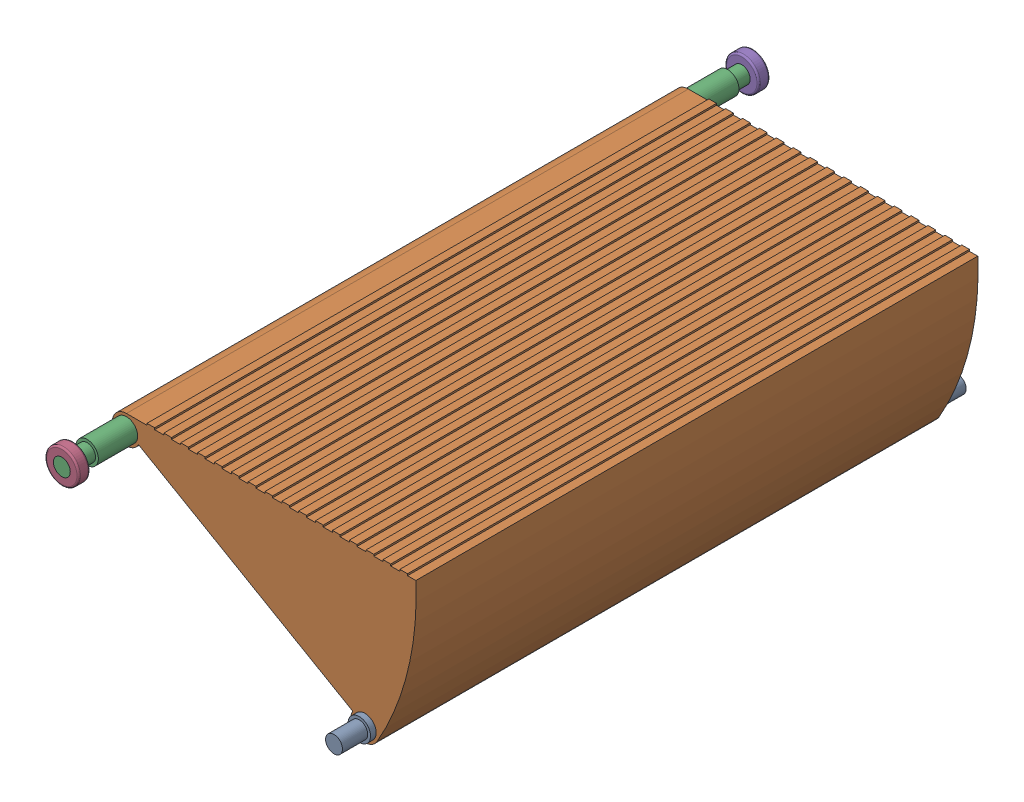
SolidWorks assembly Step assemble, configuration Default. Lengths in mm.
Overall size (545.51 300 1230).
5 component instances, 4 part files, 8 mates.
Components (placement in the parent):
- Rear axle of the step-1: Rear axle of the step [Default] at (448.7017 -218.6001 623.0736) x (0.993856 0.110677 0) z (0 0 1) size (40 40 1110)
- Step-1: Step [Varsayılan] at (448.7017 -218.6001 623.0736) size (540.51 298.02 1000)
- Front axle of the step-1: Front axle of the step [Default] at (24.3492 26.3999 623.0736) size (40 40 1230)
- Step wheel-1: Step wheel [Varsayılan] at (24.3492 26.3999 1718.0736) size (60 60 20)
- Step wheel-2: Step wheel [Varsayılan] at (24.3492 26.3999 508.0736) size (60 60 20)
Mates (geometry in assembly coordinates):
- Concentric1: concentric aligned: cylinder of Basamak-1 through (24.3492 26.3999 1623.0736) axis (0 0 -1) radius 15; cylinder of ÜstMil-1 through (24.3492 26.3999 1623.0736) axis (0 0 -1) radius 15
- Concentric2: concentric aligned: cylinder of KısaMil-1 through (448.7017 -218.6001 1623.0736) axis (0 0 -1) radius 15; cylinder of Basamak-1 through (448.7017 -218.6001 1623.0736) axis (0 0 -1) radius 25
- Width1: width anti-aligned: plane of ÜstMil-1 through (24.3492 26.3999 1738.0736) normal (0 0 1); plane of Basamak-1 through (24.3492 26.3999 508.0736) normal (0 0 -1); plane of ÜstMil-1 through (448.7017 -218.6001 623.0736) normal (0 0 -1); plane of Basamak-1 through (448.7017 -218.6001 1623.0736) normal (0 0 1)
- Width2: width anti-aligned: plane of KısaMil-1 through (448.7017 -218.6001 1678.0736) normal (0 0 1); plane of Basamak-1 through (448.7017 -218.6001 568.0736) normal (0 0 -1); plane of KısaMil-1 through (448.7017 -218.6001 623.0736) normal (0 0 -1); plane of Basamak-1 through (448.7017 -218.6001 1623.0736) normal (0 0 1)
- Concentric3: concentric aligned: cylinder of ÜstMil-1 through (24.3492 26.3999 1738.0736) axis (0 0 -1) radius 15; cylinder of Teker-1 through (24.3492 26.3999 1738.0736) axis (0 0 -1) radius 15
- Coincident1: coincident aligned: plane of ÜstMil-1 through (24.3492 26.3999 1738.0736) normal (0 0 1); plane of Teker-1 through (24.3492 26.3999 1738.0736) normal (0 0 1)
- Concentric4: concentric anti-aligned: cylinder of ÜstMil-1 through (24.3492 26.3999 508.0736) axis (0 0 1) radius 15; cylinder of Teker-2 through (24.3492 26.3999 528.0736) axis (0 0 -1) radius 15
- Coincident2: coincident aligned: plane of ÜstMil-1 through (24.3492 26.3999 508.0736) normal (0 0 -1); plane of Teker-2 through (24.3492 26.3999 508.0736) normal (0 0 -1)
